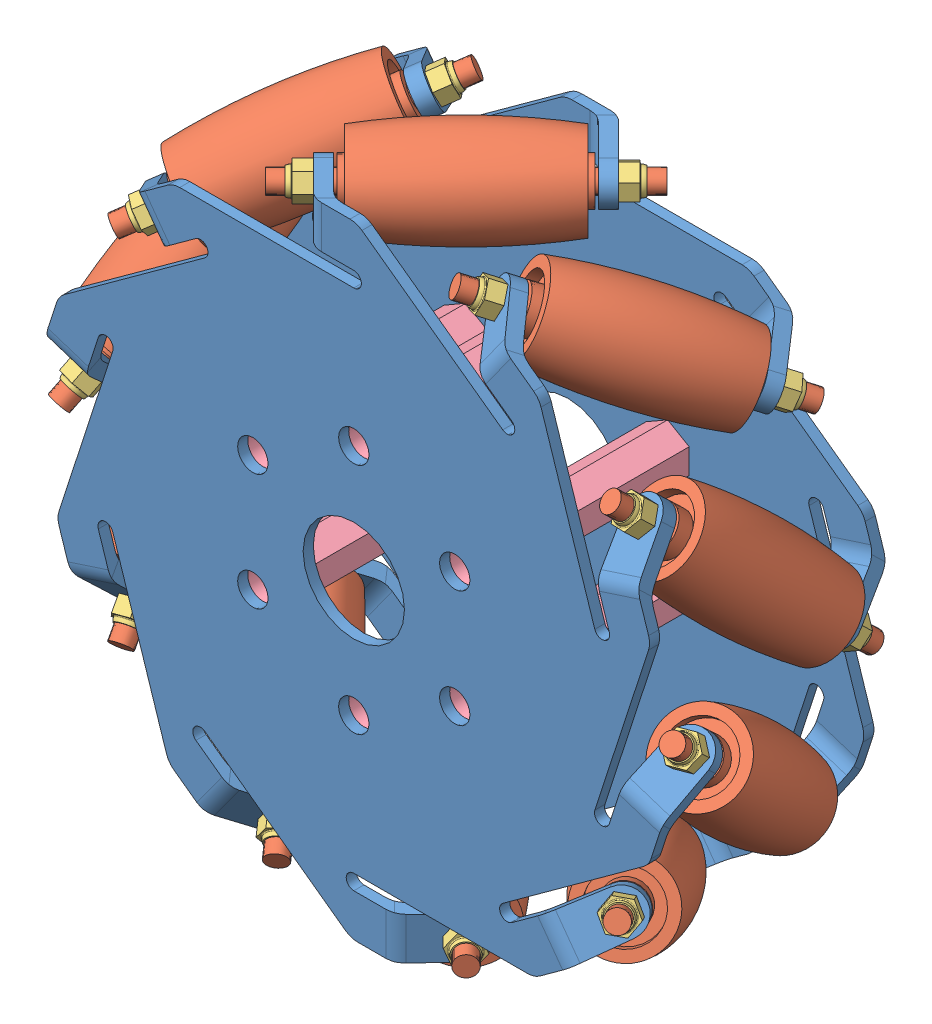
SolidWorks assembly 麦克纳姆轮装配, configuration 默认. Lengths in mm.
Overall size (73.24 68.83 28.84).
38 component instances, 4 part files, 65 mates.
Components (placement in the parent):
- 麦克纳姆轮-1: 麦克纳姆轮 [默认] at (0.4661 -9.5096 64.9154) size (62.94 61.45 5.94)
- 麦克纳姆轮-2: 麦克纳姆轮 [默认] at (0.4661 -9.5096 44.7758) x (-1 0 0) z (0 0 -1) size (62.94 61.45 5.94)
- 辊子-3: 辊子 [默认] at (-10.8507 19.0898 66.1624) x (0.707107 0 -0.707107) z (0.707107 0 0.707107) size (28 9.23 9.23)
- 辊子-4: 辊子 [默认] at (-25.5101 6.9683 66.1753) x (0.572061 0.415627 -0.707107) z (-0.42304 -0.589076 -0.688496) size (28 9.23 9.23)
- 辊子-5: 辊子 [默认] at (-30.2306 -11.4349 66.1624) x (0.218508 0.672499 -0.707107) z (0.707107 0.390255 0.589662) size (28 9.23 9.23)
- 辊子-6: 辊子 [默认] at (-23.2364 -29.1103 66.1624) x (-0.218508 0.672499 -0.707107) z (0.108472 0.736865 0.667281) size (28 9.23 9.23)
- 辊子-7: 辊子 [默认] at (-25.5101 -25.9875 43.5158) x (0.572061 -0.415627 0.707107) z (-0.707107 0.186947 0.681946) size (28 9.23 9.23)
- 辊子-8: 辊子 [默认] at (-10.8636 -38.109 43.5158) x (0.707107 0 0.707107) z (0.12537 -0.984157 -0.12537) size (28 9.23 9.23)
- 辊子-9: 辊子 [默认] at (8.1104 -39.3064 43.5158) x (0.572061 0.415627 0.707107) z (-0.707107 -0.186947 0.681946) size (28 9.23 9.23)
- 辊子-10: 辊子 [默认] at (24.1647 -29.1225 43.5158) x (0.218508 0.672499 0.707107) z (-0.707107 -0.390255 0.589662) size (28 9.23 9.23)
- 辊子-11: 辊子 [默认] at (8.1209 20.2797 66.1624) x (0.572061 -0.415627 -0.707107) z (0.707107 -0.186947 0.681946) size (28 9.23 9.23)
- 辊子-12: 辊子 [默认] at (31.1668 -11.4472 43.5158) x (-0.218508 0.672499 0.707107) z (-0.805898 -0.532961 0.25784) size (28 9.23 9.23)
- M2【螺母】-1: M2【螺母】 [默认] at (-9.3907 18.6798 46.2506) x (0.808299 -0.139279 0.572061) z (-0.572061 -0.415627 0.707107) size (2.79 3.22 1.95)
- M2【螺母】-2: M2【螺母】 [默认] at (9.0611 19.0898 46.2506) x (0.707107 0 0.707107) z (-0.707107 0 0.707107) size (2.79 3.22 1.95)
- M2【螺母】-3: M2【螺母】 [默认] at (24.2299 8.5758 46.2506) x (0.808299 0.139279 0.572061) z (-0.572061 0.415627 0.707107) size (2.79 3.22 1.95)
- M2【螺母】-4: M2【螺母】 [默认] at (30.3217 -8.8462 46.2506) x (0.972031 0.086079 0.218508) z (-0.218508 0.672499 0.707107) size (2.79 3.22 1.95)
- M2【螺母】-5: M2【螺母】 [默认] at (25.0098 -26.5216 46.2506) x (0.972031 -0.086079 -0.218508) z (0.218508 0.672499 0.707107) size (2.79 3.22 1.95)
- M2【螺母】-6: M2【螺母】 [默认] at (10.323 -37.699 46.2506) x (0.808299 -0.139279 -0.572061) z (0.572061 0.415627 0.707107) size (2.79 3.22 1.95)
- M2【螺母】-7: M2【螺母】 [默认] at (-8.1288 -38.109 46.2506) x (0.707107 0 -0.707107) z (0.707107 0 0.707107) size (2.79 3.22 1.95)
- M2【螺母】-8: M2【螺母】 [默认] at (-23.2976 -27.595 46.2506) x (0.808299 0.139279 -0.572061) z (0.572061 -0.415627 0.707107) size (2.79 3.22 1.95)
- M2【螺母】-9: M2【螺母】 [默认] at (-29.3895 -10.173 46.2506) x (0.972031 0.086079 -0.218508) z (0.218508 -0.672499 0.707107) size (2.79 3.22 1.95)
- M2【螺母】-10: M2【螺母】 [默认] at (-24.0775 7.5024 46.2506) x (0.972031 -0.086079 0.218508) z (-0.218508 -0.672499 0.707107) size (2.79 3.22 1.95)
- M2【螺母】-11: M2【螺母】 [默认] at (30.3217 -10.173 63.4405) x (-0.703826 -0.39331 0.591554) z (-0.218508 -0.672499 -0.707107) size (2.79 3.22 1.95)
- M2【螺母】-13: M2【螺母】 [默认] at (25.0098 7.5024 63.4405) x (0.835211 -0.245852 0.491913) z (0.218508 -0.672499 -0.707107) size (2.79 3.22 1.95)
- M2【螺母】-14: M2【螺母】 [默认] at (10.323 18.6798 63.4405) x (0.731274 -0.131986 0.669192) z (0.572061 -0.415627 -0.707107) size (2.79 3.22 1.95)
- M2【螺母】-15: M2【螺母】 [默认] at (-8.1288 19.0898 63.4405) x (0.610509 -0.504536 0.610509) z (0.707107 0 -0.707107) size (2.79 3.22 1.95)
- M2【螺母】-16: M2【螺母】 [默认] at (-23.2976 8.5758 63.4405) x (0.785961 -0.524301 0.327679) z (0.572061 0.415627 -0.707107) size (2.79 3.22 1.95)
- M2【螺母】-17: M2【螺母】 [默认] at (-29.3895 -8.8462 63.4405) x (0.874876 -0.455982 -0.163313) z (0.218508 0.672499 -0.707107) size (2.79 3.22 1.95)
- M2【螺母】-18: M2【螺母】 [默认] at (-24.0775 -26.5216 63.4405) x (0.829372 -0.253837 -0.497703) z (-0.218508 0.672499 -0.707107) size (2.79 3.22 1.95)
- M2【螺母】-19: M2【螺母】 [默认] at (-9.3907 -37.699 63.4405) x (0.565426 -0.424684 -0.707062) z (-0.572061 0.415627 -0.707107) size (2.79 3.22 1.95)
- M2【螺母】-20: M2【螺母】 [默认] at (9.0611 -38.109 63.4405) x (0.556393 -0.617133 -0.556393) z (-0.707107 0 -0.707107) size (2.79 3.22 1.95)
- M2【螺母】-21: M2【螺母】 [默认] at (24.2299 -27.595 63.4405) x (0.779137 -0.544759 -0.310134) z (-0.572061 -0.415627 -0.707107) size (2.79 3.22 1.95)
- 20mm长-M3【六角铜柱】-1: 20mm长-M3【六角铜柱】 [默认] at (-9.4932 -3.7596 44.9154) size (4.27 4.93 20)
- 20mm长-M3【六角铜柱】-2: 20mm长-M3【六角铜柱】 [默认] at (-9.4932 -15.2596 44.9154) x (0.5 0.866025 0) z (0 0 1) size (4.27 4.93 20)
- 20mm长-M3【六角铜柱】-3: 20mm长-M3【六角铜柱】 [默认] at (0.4661 -21.0096 44.9154) x (-0.5 0.866025 0) z (0 0 1) size (4.27 4.93 20)
- 20mm长-M3【六角铜柱】-4: 20mm长-M3【六角铜柱】 [默认] at (10.4254 -15.2596 44.9154) x (-1 0 0) z (0 0 1) size (4.27 4.93 20)
- 20mm长-M3【六角铜柱】-5: 20mm长-M3【六角铜柱】 [默认] at (10.4254 -3.7596 44.9154) x (-0.5 -0.866025 0) z (0 0 1) size (4.27 4.93 20)
- 20mm长-M3【六角铜柱】-6: 20mm长-M3【六角铜柱】 [默认] at (0.4661 1.9904 44.9154) x (0.5 -0.866025 0) z (0 0 1) size (4.27 4.93 20)
Mates (geometry in assembly coordinates):
- 同心1: concentric: cylinder of assembly; cylinder of assembly; cylinder of 麦克纳姆轮-1 through (0.4661 -9.5096 64.9154) axis (0 0 1) radius 5; cylinder of 麦克纳姆轮-2 through (0.4661 -9.5096 44.7758) axis (0 0 -1) radius 5
- 距离2: distance = 0.25 mm: plane of assembly; plane of assembly; plane of 麦克纳姆轮-1 through (-7.4824 21.1891 59.9656) normal (0.707107 0 -0.707107); plane of 辊子-3 through (-5.8914 19.0898 61.2031) normal (-0.707107 0 0.707107)
- 同心4: concentric: cylinder of assembly; cylinder of assembly; cylinder of 麦克纳姆轮-1 through (-4.9468 19.0898 60.2585) axis (-0.707107 0 0.707107) radius 1; cylinder of 辊子-3 through (-9.4269 19.0898 64.7386) axis (0.707107 0 -0.707107) radius 1
- 同心5: concentric: cylinder of assembly; cylinder of assembly; cylinder of 麦克纳姆轮-2 through (5.8791 19.0898 49.4326) axis (0.707107 0 -0.707107) radius 1; cylinder of 辊子-3 through (10.3721 19.0898 44.9396) axis (-0.707107 0 0.707107) radius 1
- 同心6: concentric: cylinder of assembly; cylinder of assembly; cylinder of 麦克纳姆轮-1 through (-20.7233 10.4461 60.2585) axis (-0.572061 -0.415627 0.707107) radius 1; cylinder of 辊子-4 through (-24.3582 7.8052 64.7515) axis (0.572061 0.415627 -0.707107) radius 1
- 同心7: concentric: cylinder of assembly; cylinder of assembly; cylinder of 麦克纳姆轮-2 through (-11.965 16.8094 49.4326) axis (0.572061 0.415627 -0.707107) radius 1; cylinder of 辊子-4 through (-8.3405 19.4428 44.9525) axis (-0.572061 -0.415627 0.707107) radius 1
- 距离1: distance = 0.25 mm: plane of assembly; plane of assembly; plane of 麦克纳姆轮-2 through (-11.1477 19.9982 49.7255) normal (-0.572061 -0.415627 0.707107); plane of 辊子-4 through (-11.2008 17.3646 48.4881) normal (0.572061 0.415627 -0.707107)
- 同心10: concentric: cylinder of assembly; cylinder of assembly; cylinder of 麦克纳姆轮-1 through (-28.4062 -5.8199 60.2585) axis (-0.218508 -0.672499 0.707107) radius 1; cylinder of 辊子-5 through (-29.7906 -10.0808 64.7386) axis (0.218508 0.672499 -0.707107) radius 1
- 距离4: distance = 0.25 mm: plane of assembly; plane of assembly; plane of 麦克纳姆轮-1 through (-31.1863 -7.5826 59.9656) normal (0.218508 0.672499 -0.707107); plane of 辊子-5 through (-28.6981 -6.7183 61.2031) normal (-0.218508 -0.672499 0.707107)
- 同心11: concentric: cylinder of assembly; cylinder of assembly; cylinder of 麦克纳姆轮-1 through (-25.0608 -23.4953 60.2585) axis (0.218508 -0.672499 0.707107) radius 1; cylinder of 辊子-6 through (-23.6764 -27.7561 64.7386) axis (-0.218508 0.672499 -0.707107) radius 1
- 距离5: distance = 0.25 mm: plane of assembly; plane of assembly; plane of 麦克纳姆轮-1 through (-26.2739 -26.5555 59.9656) normal (-0.218508 0.672499 -0.707107); plane of 辊子-6 through (-24.7689 -24.3936 61.2031) normal (0.218508 -0.672499 0.707107)
- 同心12: concentric: cylinder of assembly; cylinder of assembly; cylinder of 麦克纳姆轮-1 through (-11.965 -35.8286 60.2585) axis (0.572061 -0.415627 0.707107) radius 1; cylinder of 辊子-7 through (-8.3405 -38.462 64.7386) axis (-0.572061 0.415627 -0.707107) radius 1
- 距离6: distance = 0.25 mm: plane of assembly; plane of assembly; plane of 麦克纳姆轮-1 through (-11.1477 -39.0174 59.9656) normal (-0.572061 0.415627 -0.707107); plane of 辊子-7 through (-11.2008 -36.3838 61.2031) normal (0.572061 -0.415627 0.707107)
- 同心13: concentric: cylinder of assembly; cylinder of assembly; cylinder of 麦克纳姆轮-1 through (5.8791 -38.109 60.2585) axis (0.707107 0 0.707107) radius 1; cylinder of 辊子-8 through (10.3592 -38.109 64.7386) axis (-0.707107 0 -0.707107) radius 1
- 距离7: distance = 0.25 mm: plane of assembly; plane of assembly; plane of 麦克纳姆轮-1 through (8.4146 -40.2083 59.9656) normal (-0.707107 0 -0.707107); plane of 辊子-8 through (6.8236 -38.109 61.2031) normal (0.707107 0 0.707107)
- 同心14: concentric: cylinder of assembly; cylinder of assembly; cylinder of 麦克纳姆轮-1 through (21.6556 -29.4653 60.2585) axis (0.572061 0.415627 0.707107) radius 1; cylinder of 辊子-9 through (25.2801 -26.832 64.7386) axis (-0.572061 -0.415627 -0.707107) radius 1
- 距离8: distance = 0.25 mm: plane of assembly; plane of assembly; plane of 麦克纳姆轮-1 through (24.9409 -29.6734 59.9656) normal (-0.572061 -0.415627 -0.707107); plane of 辊子-9 through (22.4198 -28.9101 61.2031) normal (0.572061 0.415627 0.707107)
- 同心15: concentric: cylinder of assembly; cylinder of assembly; cylinder of 麦克纳姆轮-1 through (29.3384 -13.1993 60.2585) axis (0.218508 0.672499 0.707107) radius 1; cylinder of 辊子-10 through (30.7229 -8.9385 64.7386) axis (-0.218508 -0.672499 -0.707107) radius 1
- 距离9: distance = 0.25 mm: plane of assembly; plane of assembly; plane of 辊子-10 through (29.6303 -12.3009 61.2031) normal (0.218508 0.672499 0.707107); plane of 麦克纳姆轮-1 through (32.1186 -11.4366 59.9656) normal (-0.218508 -0.672499 -0.707107)
- 同心16: concentric: cylinder of assembly; cylinder of assembly; cylinder of 麦克纳姆轮-1 through (12.8972 16.8094 60.2585) axis (-0.572061 0.415627 0.707107) radius 1; cylinder of 辊子-11 through (9.2728 19.4428 64.7386) axis (0.572061 -0.415627 -0.707107) radius 1
- 距离10: distance = 0.25 mm: plane of assembly; plane of assembly; plane of 麦克纳姆轮-1 through (12.0799 19.9982 59.9656) normal (0.572061 -0.415627 -0.707107); plane of 辊子-11 through (12.1331 17.3646 61.2031) normal (-0.572061 0.415627 0.707107)
- 同心17: concentric: cylinder of assembly; cylinder of assembly; cylinder of 麦克纳姆轮-1 through (25.9931 4.4761 60.2585) axis (-0.218508 0.672499 0.707107) radius 1; cylinder of 辊子-12 through (24.6086 8.7369 64.7386) axis (0.218508 -0.672499 -0.707107) radius 1
- 距离11: distance = 0.25 mm: plane of assembly; plane of assembly; plane of 辊子-12 through (25.7012 5.3744 61.2031) normal (-0.218508 0.672499 0.707107); plane of 麦克纳姆轮-1 through (27.2061 7.5363 59.9656) normal (0.218508 -0.672499 -0.707107)
- 同心18: concentric: cylinder of assembly; cylinder of assembly; cylinder of 辊子-4 through (-8.3405 19.4428 44.9525) axis (-0.572061 -0.415627 0.707107) radius 1; cylinder of M2【螺母】-1 through (-10.2488 18.0563 47.3113) axis (0.572061 0.415627 -0.707107) radius 1
- 重合1: coincident: plane of assembly; plane of assembly; plane of 麦克纳姆轮-2 through (-7.8707 17.1891 48.7255) normal (0.572061 0.415627 -0.707107); plane of M2【螺母】-1 through (-10.2488 18.0563 47.3113) normal (-0.572061 -0.415627 0.707107)
- 同心19: concentric: cylinder of assembly; cylinder of assembly; cylinder of 辊子-3 through (10.3721 19.0898 44.9396) axis (-0.707107 0 0.707107) radius 1; cylinder of M2【螺母】-2 through (8.0004 19.0898 47.3113) axis (0.707107 0 -0.707107) radius 1
- 重合2: coincident: plane of 麦克纳姆轮-2 through (9.4146 16.9904 48.7255) normal (0.707107 0 -0.707107); plane of M2【螺母】-2 through (8.0004 19.0898 47.3113) normal (-0.707107 0 0.707107)
- 同心20: concentric: cylinder of assembly; cylinder of assembly; cylinder of 辊子-11 through (25.2905 7.8052 44.9396) axis (-0.572061 0.415627 0.707107) radius 1; cylinder of M2【螺母】-3 through (23.3718 9.1992 47.3113) axis (0.572061 -0.415627 -0.707107) radius 1
- 重合3: coincident: plane of 麦克纳姆轮-2 through (23.2819 6.6696 48.7255) normal (0.572061 -0.415627 -0.707107); plane of M2【螺母】-3 through (23.3718 9.1992 47.3113) normal (-0.572061 0.415627 0.707107)
- 同心21: concentric: cylinder of assembly; cylinder of assembly; cylinder of 辊子-12 through (30.7269 -10.093 44.9396) axis (-0.218508 0.672499 0.707107) radius 1; cylinder of M2【螺母】-4 through (29.994 -7.8374 47.3113) axis (0.218508 -0.672499 -0.707107) radius 1
- 重合4: coincident: plane of 麦克纳姆轮-2 through (28.4344 -9.8312 48.7255) normal (0.218508 -0.672499 -0.707107); plane of M2【螺母】-4 through (29.994 -7.8374 47.3113) normal (-0.218508 0.672499 0.707107)
- 同心22: concentric: cylinder of assembly; cylinder of assembly; cylinder of 辊子-10 through (24.6046 -27.7684 44.9396) axis (0.218508 0.672499 0.707107) radius 1; cylinder of M2【螺母】-5 through (25.3375 -25.5128 47.3113) axis (-0.218508 -0.672499 -0.707107) radius 1
- 重合5: coincident: plane of 麦克纳姆轮-2 through (22.9039 -26.2091 48.7255) normal (-0.218508 -0.672499 -0.707107); plane of M2【螺母】-5 through (25.3375 -25.5128 47.3113) normal (0.218508 0.672499 0.707107)
- 同心23: concentric: cylinder of assembly; cylinder of assembly; cylinder of 辊子-9 through (9.2623 -38.4695 44.9396) axis (0.572061 0.415627 0.707107) radius 1; cylinder of M2【螺母】-6 through (11.1811 -37.0755 47.3113) axis (-0.572061 -0.415627 -0.707107) radius 1
- 重合6: coincident: plane of 麦克纳姆轮-2 through (8.803 -36.2083 48.7255) normal (-0.572061 -0.415627 -0.707107); plane of M2【螺母】-6 through (11.1811 -37.0755 47.3113) normal (0.572061 0.415627 0.707107)
- 同心24: concentric: cylinder of assembly; cylinder of assembly; cylinder of 辊子-8 through (-9.4398 -38.109 44.9396) axis (0.707107 0 0.707107) radius 1; cylinder of M2【螺母】-7 through (-7.0681 -38.109 47.3113) axis (-0.707107 0 -0.707107) radius 1
- 重合7: coincident: plane of 麦克纳姆轮-2 through (-8.4824 -36.0096 48.7255) normal (-0.707107 0 -0.707107); plane of M2【螺母】-7 through (-7.0681 -38.109 47.3113) normal (0.707107 0 0.707107)
- 同心25: concentric: cylinder of assembly; cylinder of assembly; cylinder of 辊子-7 through (-24.3582 -26.8244 44.9396) axis (0.572061 -0.415627 0.707107) radius 1; cylinder of M2【螺母】-8 through (-22.4395 -28.2184 47.3113) axis (-0.572061 0.415627 -0.707107) radius 1
- 重合8: coincident: plane of 麦克纳姆轮-2 through (-22.3497 -25.6888 48.7255) normal (-0.572061 0.415627 -0.707107); plane of M2【螺母】-8 through (-22.4395 -28.2184 47.3113) normal (0.572061 -0.415627 0.707107)
- 同心26: concentric: cylinder of assembly; cylinder of assembly; cylinder of 辊子-6 through (-29.7946 -8.9262 44.9396) axis (0.218508 -0.672499 0.707107) radius 1; cylinder of M2【螺母】-9 through (-29.0617 -11.1818 47.3113) axis (-0.218508 0.672499 -0.707107) radius 1
- 重合9: coincident: plane of 麦克纳姆轮-2 through (-27.5021 -9.188 48.7255) normal (-0.218508 0.672499 -0.707107); plane of M2【螺母】-9 through (-29.0617 -11.1818 47.3113) normal (0.218508 -0.672499 0.707107)
- 同心27: concentric: cylinder of assembly; cylinder of assembly; cylinder of 辊子-5 through (-23.6724 8.7492 44.9396) axis (-0.218508 -0.672499 0.707107) radius 1; cylinder of M2【螺母】-10 through (-24.4053 6.4936 47.3113) axis (0.218508 0.672499 -0.707107) radius 1
- 重合10: coincident: plane of 麦克纳姆轮-2 through (-21.9716 7.1899 48.7255) normal (0.218508 0.672499 -0.707107); plane of M2【螺母】-10 through (-24.4053 6.4936 47.3113) normal (-0.218508 -0.672499 0.707107)
- 同心28: concentric: cylinder of assembly; cylinder of assembly; cylinder of 辊子-10 through (30.7229 -8.9385 64.7386) axis (-0.218508 -0.672499 -0.707107) radius 1; cylinder of M2【螺母】-11 through (29.994 -11.1818 62.3799) axis (0.218508 0.672499 0.707107) radius 1
- 重合13: coincident: plane of 麦克纳姆轮-1 through (28.4344 -9.188 60.9656) normal (0.218508 0.672499 0.707107); plane of M2【螺母】-11 through (29.994 -11.1818 62.3799) normal (-0.218508 -0.672499 -0.707107)
- 同心32: concentric: cylinder of assembly; cylinder of assembly; cylinder of 辊子-12 through (24.6086 8.7369 64.7386) axis (0.218508 -0.672499 -0.707107) radius 1; cylinder of M2【螺母】-13 through (25.3375 6.4936 62.3799) axis (-0.218508 0.672499 0.707107) radius 1
- 同心33: concentric: cylinder of assembly; cylinder of assembly; cylinder of 辊子-11 through (9.2728 19.4428 64.7386) axis (0.572061 -0.415627 -0.707107) radius 1; cylinder of M2【螺母】-14 through (11.1811 18.0563 62.3799) axis (-0.572061 0.415627 0.707107) radius 1
- 同心34: concentric: cylinder of assembly; cylinder of assembly; cylinder of 辊子-3 through (-9.4269 19.0898 64.7386) axis (0.707107 0 -0.707107) radius 1; cylinder of M2【螺母】-15 through (-7.0681 19.0898 62.3799) axis (-0.707107 0 0.707107) radius 1
- 同心35: concentric: cylinder of assembly; cylinder of assembly; cylinder of 辊子-4 through (-24.3582 7.8052 64.7515) axis (0.572061 0.415627 -0.707107) radius 1; cylinder of M2【螺母】-16 through (-22.4395 9.1992 62.3799) axis (-0.572061 -0.415627 0.707107) radius 1
- 同心36: concentric: cylinder of assembly; cylinder of assembly; cylinder of 辊子-5 through (-29.7906 -10.0808 64.7386) axis (0.218508 0.672499 -0.707107) radius 1; cylinder of M2【螺母】-17 through (-29.0617 -7.8374 62.3799) axis (-0.218508 -0.672499 0.707107) radius 1
- 同心37: concentric: cylinder of assembly; cylinder of assembly; cylinder of 辊子-6 through (-23.6764 -27.7561 64.7386) axis (-0.218508 0.672499 -0.707107) radius 1; cylinder of M2【螺母】-18 through (-24.4053 -25.5128 62.3799) axis (0.218508 -0.672499 0.707107) radius 1
- 同心38: concentric: cylinder of assembly; cylinder of assembly; cylinder of 辊子-7 through (-8.3405 -38.462 64.7386) axis (-0.572061 0.415627 -0.707107) radius 1; cylinder of M2【螺母】-19 through (-10.2488 -37.0755 62.3799) axis (0.572061 -0.415627 0.707107) radius 1
- 同心39: concentric: cylinder of assembly; cylinder of assembly; cylinder of 辊子-8 through (10.3592 -38.109 64.7386) axis (-0.707107 0 -0.707107) radius 1; cylinder of M2【螺母】-20 through (8.0004 -38.109 62.3799) axis (0.707107 0 0.707107) radius 1
- 同心40: concentric: cylinder of assembly; cylinder of assembly; cylinder of 辊子-9 through (25.2801 -26.832 64.7386) axis (-0.572061 -0.415627 -0.707107) radius 1; cylinder of M2【螺母】-21 through (23.3718 -28.2184 62.3799) axis (0.572061 0.415627 0.707107) radius 1
- 重合14: coincident: plane of 麦克纳姆轮-1 through (23.2819 -25.6888 60.9656) normal (0.572061 0.415627 0.707107); plane of M2【螺母】-21 through (23.3718 -28.2184 62.3799) normal (-0.572061 -0.415627 -0.707107)
- 重合15: coincident: plane of 麦克纳姆轮-1 through (9.4146 -36.0096 60.9656) normal (0.707107 0 0.707107); plane of M2【螺母】-20 through (8.0004 -38.109 62.3799) normal (-0.707107 0 -0.707107)
- 重合16: coincident: plane of 麦克纳姆轮-1 through (-7.8707 -36.2083 60.9656) normal (0.572061 -0.415627 0.707107); plane of M2【螺母】-19 through (-10.2488 -37.0755 62.3799) normal (-0.572061 0.415627 -0.707107)
- 重合17: coincident: plane of 麦克纳姆轮-1 through (-21.9716 -26.2091 60.9656) normal (0.218508 -0.672499 0.707107); plane of M2【螺母】-18 through (-24.4053 -25.5128 62.3799) normal (-0.218508 0.672499 -0.707107)
- 重合18: coincident: plane of 麦克纳姆轮-1 through (-27.5021 -9.8312 60.9656) normal (-0.218508 -0.672499 0.707107); plane of M2【螺母】-17 through (-29.0617 -7.8374 62.3799) normal (0.218508 0.672499 -0.707107)
- 重合19: coincident: plane of 麦克纳姆轮-1 through (-22.3497 6.6696 60.9656) normal (-0.572061 -0.415627 0.707107); plane of M2【螺母】-16 through (-22.4395 9.1992 62.3799) normal (0.572061 0.415627 -0.707107)
- 重合20: coincident: plane of 麦克纳姆轮-1 through (-8.4824 16.9904 60.9656) normal (-0.707107 0 0.707107); plane of M2【螺母】-15 through (-7.0681 19.0898 62.3799) normal (0.707107 0 -0.707107)
- 重合21: coincident: plane of 麦克纳姆轮-1 through (8.803 17.1891 60.9656) normal (-0.572061 0.415627 0.707107); plane of M2【螺母】-14 through (11.1811 18.0563 62.3799) normal (0.572061 -0.415627 -0.707107)
- 重合22: coincident: plane of 麦克纳姆轮-1 through (22.9039 7.1899 60.9656) normal (-0.218508 0.672499 0.707107); plane of M2【螺母】-13 through (25.3375 6.4936 62.3799) normal (0.218508 -0.672499 -0.707107)
- 同心41: concentric: cylinder of assembly; cylinder of assembly; cylinder of 麦克纳姆轮-1 through (-9.4932 -3.7596 64.9154) axis (0 0 1) radius 1.5; cylinder of 20mm长-M3【六角铜柱】-1 through (-9.4932 -3.7596 64.9154) axis (0 0 -1) radius 1.5
- 重合23: coincident: plane of assembly; plane of assembly; plane of 麦克纳姆轮-1 through (0.4661 16.2404 64.9154) normal (0 0 -1); plane of 20mm长-M3【六角铜柱】-1 through (-9.4932 -3.7596 64.9154) normal (0 0 1)
